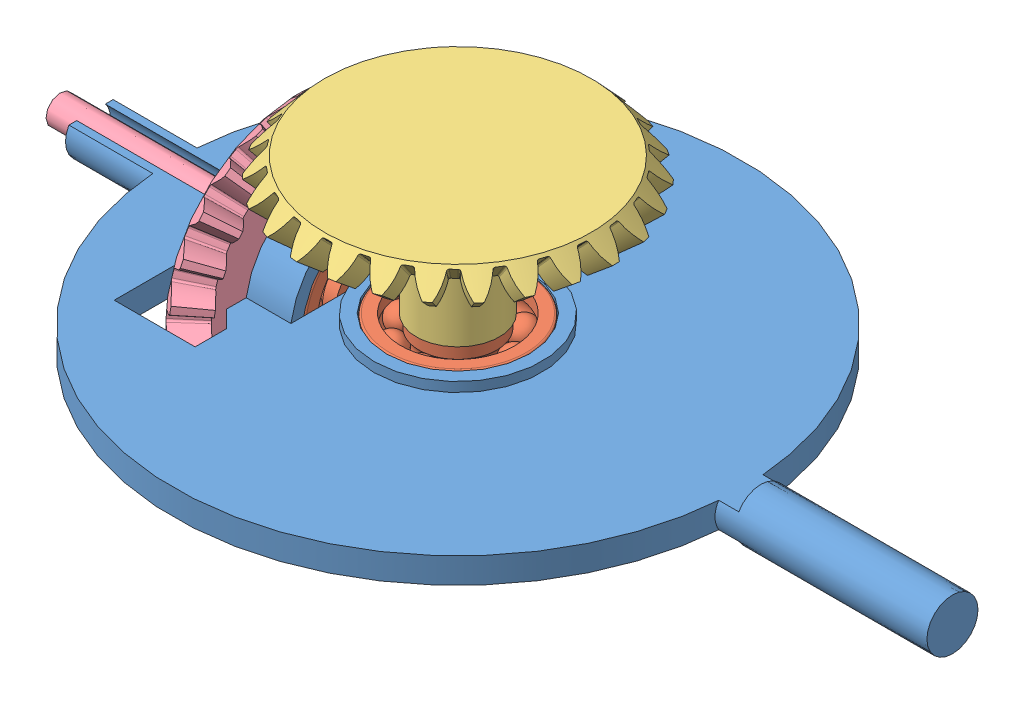
SolidWorks assembly Plate, configuration Default. Lengths in mm.
Overall size (139.7 49.71 88.9).
5 component instances, 4 part files, 9 mates.
Components (placement in the parent):
- Plate-1: Plate [Default] at origin size (132.2 26.3 88.9)
- instrument ball bearing_68_am-1: instrument ball bearing_68_am [AFBMA 12.1.4.1 - 0080-22 - 8,DE,NC,8_68] x (0 -1 0) z (0.546944 0 -0.837169) size (7 22 22)
- instrument ball bearing_68_am-2: instrument ball bearing_68_am [AFBMA 12.1.4.1 - 0080-22 - 8,DE,NC,8_68] at (-16.65 0 0) size (7 22 22)
- BallShaft2-2: BallShaft2 [Metric - Straight bevel gear 1.75M 26GT 24PT 20PA 5FW ---26O8H10MD5N] at (0 24.8676 0) x (0 -1 0) z (-0.773591 0 -0.633685) size (28.37 47.64 47.86)
- YawShaft2-3: YawShaft2 [Metric - Straight bevel gear 1.75M 26GT 24PT 20PA 5FW ---26O8H10MD5N] at (-24.8676 0 0) x (1 0 0) z (0 -0.043825 0.999039) size (49.1 47.64 47.86)
Mates (geometry in assembly coordinates):
- Width1: width: plane of instrument ball bearing_68_am-1 through (-7.4508 3.5 -4.8678) normal (0 1 0); plane of instrument ball bearing_68_am-1 through (-8.9577 -3.5 -5.8523) normal (0 -1 0); plane of Plate-1 through (0 3.5 0) normal (0 1 0); plane of Plate-1 through (0 -3.5 0) normal (0 -1 0)
- Concentric1: concentric: cylinder of Plate-1 through (0 3.5 0) axis (0 -1 0) radius 11.15; cylinder of instrument ball bearing_68_am-1 through (0 20.6375 0) axis (0 -1 0) radius 4
- Concentric2: concentric: cylinder of Plate-1 through (-20.15 0 0) axis (1 0 0) radius 11.15; cylinder of instrument ball bearing_68_am-2 through (-37.2875 0 0) axis (1 0 0) radius 4
- Width2: width: plane of instrument ball bearing_68_am-2 through (-20.15 8.9 0) normal (-1 0 0); plane of instrument ball bearing_68_am-2 through (-13.15 10.7 0) normal (1 0 0); plane of Plate-1 through (-13.15 0 0) normal (1 0 0); plane of Plate-1 through (-20.15 0 0) normal (-1 0 0)
- Concentric3: concentric: cylinder of instrument ball bearing_68_am-1 through (0 20.6375 0) axis (0 -1 0) radius 4; cylinder of BallShaft2-2 through (0 -3.5 0) axis (0 1 0) radius 4
- Coincident3: coincident: plane of instrument ball bearing_68_am-1 through (-3.5998 -3.5 -2.3519) normal (0 -1 0); plane of BallShaft2-2 through (0 -3.5 0) normal (0 -1 0)
- Coincident4: coincident: plane of Plate-1 through (-20.15 0 0) normal (-1 0 0); plane of YawShaft2-3 through (-20.15 0 0) normal (1 0 0)
- Concentric4: concentric: cylinder of instrument ball bearing_68_am-2 through (-37.2875 0 0) axis (1 0 0) radius 4; cylinder of YawShaft2-3 through (-13.15 0 0) axis (-1 0 0) radius 4
- GearMate1: gear = 13 : 13 mm: cylinder of YawShaft2-3 through (-13.15 0 0) axis (-1 0 0) radius 4; cylinder of BallShaft2-2 through (0 -14.8848 0) axis (0 1 0) radius 6.5
